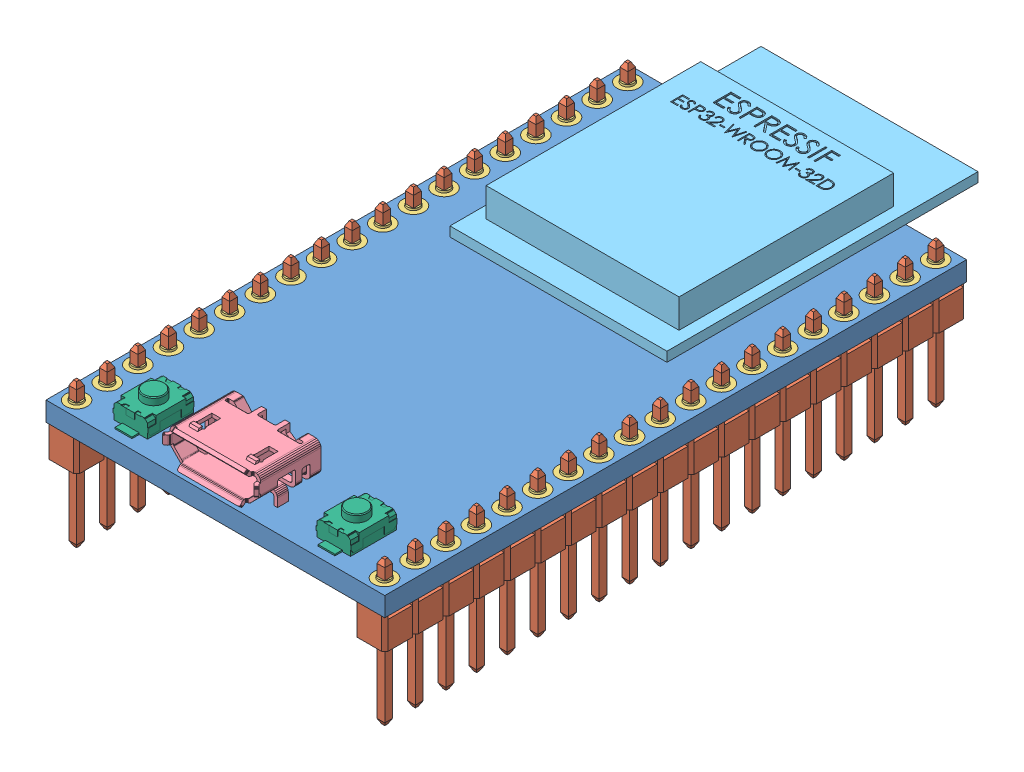
SolidWorks assembly ESP32-WROOM-32D-Assembly, configuration Default. Lengths in mm.
Overall size (28.1 14.23 54.86).
8 component instances, 6 part files, 27 mates.
Components (placement in the parent):
- Main-PCB-1: Main-PCB [Default] x (1 0 0) z (0 1 0) size (28.1 48.26 1.6)
- zl201-19_p2-54_l48-3_w2-54_h8-9-1: zl201-19_p2-54_l48-3_w2-54_h8-9 [Default] at (-12.78 -0.25 22.86) x (0 0 1) z (0 -1 0) size (48.26 2.54 11.94)
- zl201-19_p2-54_l48-3_w2-54_h8-9-2: zl201-19_p2-54_l48-3_w2-54_h8-9 [Default] at (12.78 -0.25 -22.86) x (0 0 -1) z (0 -1 0) size (48.26 2.54 11.94)
- Soldering-Contacts-1: Soldering-Contacts [Default] at (0 1.6 0) x (1 0 0) z (0 1 0) size (27.34 47.52 2)
- ab2_usb_micro_smd.wrl-1: ab2_usb_micro_smd.wrl [Default] at (0 2.585 24.73) x (1 0 0) z (0 1 0) size (8 5.6 3.57)
- ESP32-chip-1: ESP32-chip [Default] at (0 1.6 0) x (1 0 0) z (0 1 0) size (18 25.8 3.2)
- 3x4x2mm_tact_button-1: 3x4x2mm_tact_button [Default] at (9.1347 1.6 18.3459) x (0 0 1) z (-1 0 0) size (5 2 2.9)
- 3x4x2mm_tact_button-2: 3x4x2mm_tact_button [Default] at (-7.7053 1.6 18.3459) x (0 0 1) z (-1 0 0) size (5 2 2.9)
Mates (geometry in assembly coordinates):
- На месте1: in place: plane of Main-PCB-1 through (0 0 0) normal (0 1 0); moOrthogonalPlaneRef_w of Main-PCB-1 through (0 0 0) normal (0 0 -1); plane of Main-PCB-1 through (0 0 0) normal (1 0 0); unknown of Main-PCB-1
- Совпадение1: coincident aligned: 
- Совпадение2: coincident aligned: plane of Деталь1^Сборка1-1 through (0 0 0) normal (0 0 -1)
- Совпадение3: coincident anti-aligned: plane of Деталь1^Сборка1-1 through (0 0 0) normal (1 0 0)
- Совпадение4: coincident aligned: plane of Деталь1^Сборка1-1 through (-14.05 1.6 -24.13) normal (0 0 -1); plane of zl201-19_p2-54_l48-3_w2-54_h8-9-2 through (13.8 -2.54 -24.13) normal (0 0 -1)
- Совпадение5: coincident anti-aligned: plane of Деталь1^Сборка1-1 through (0 0 0) normal (0 -1 0); plane of zl201-19_p2-54_l48-3_w2-54_h8-9-2 through (12.78 0 -22.86) normal (0 1 0)
- Совпадение6: coincident aligned: plane of Деталь1^Сборка1-1 through (14.05 1.6 24.13) normal (1 0 0); plane of zl201-19_p2-54_l48-3_w2-54_h8-9-2 through (14.05 -2.54 -21.84) normal (1 0 0)
- Совпадение7: coincident aligned: plane of Деталь1^Сборка1-1 through (-14.05 1.6 -24.13) normal (0 0 -1); plane of zl201-19_p2-54_l48-3_w2-54_h8-9-1 through (-13.8 -2.54 -24.13) normal (0 0 -1)
- Совпадение8: coincident aligned: plane of Деталь1^Сборка1-1 through (-14.05 1.6 24.13) normal (-1 0 0); plane of zl201-19_p2-54_l48-3_w2-54_h8-9-1 through (-14.05 -2.54 -23.88) normal (-1 0 0)
- Совпадение9: coincident anti-aligned: plane of Деталь1^Сборка1-1 through (0 0 0) normal (0 -1 0); plane of zl201-19_p2-54_l48-3_w2-54_h8-9-1 through (-12.78 0 -22.86) normal (0 1 0)
- На месте2: in place: plane of Main-PCB-1 through (0 1.6 0) normal (0 1 0); plane of ? through (0 1.6 0) normal (0 1 0); plane of Main-PCB-1 through (0 1.6 0) normal (0 1 0); plane of ? through (0 1.6 0) normal (0 0 -1); plane of Main-PCB-1 through (0 1.6 0) normal (0 1 0); plane of ? through (0 1.6 0) normal (1 0 0); plane of Main-PCB-1 through (0 1.6 0) normal (0 1 0); unknown of ?
- Совпадение10: coincident aligned: plane of ?; plane of ?
- Совпадение11: coincident aligned: plane of Деталь1^ESP-WROOM-32D-Сборка-1 through (0 1.6 0) normal (0 0 -1); plane of Олово-Пайки-Ножек^ESP-WROOM-32D-Сборка-1 through (0 1.6 0) normal (0 0 -1)
- Совпадение12: coincident anti-aligned: plane of Деталь1^ESP-WROOM-32D-Сборка-1 through (0 1.6 0) normal (-1 0 0); plane of Олово-Пайки-Ножек^ESP-WROOM-32D-Сборка-1 through (0 1.6 0) normal (1 0 0)
- Расстояние6: distance = 1 mm anti-aligned: plane of Основная-Плата-1 through (0 1.6 0) normal (0 1 0); plane of ab2_usb_micro_smd.wrl-1 through (0 2.6 24.73) normal (0 -1 0)
- Совпадение14: coincident aligned: plane of Основная-Плата-1 through (-14.05 1.6 24.13) normal (0 0 1); plane of ab2_usb_micro_smd.wrl-1 through (0 2.585 24.13) normal (0 0 1)
- Совпадение15: coincident aligned: plane of Основная-Плата-1 through (0 0 0) normal (1 0 0); plane of ab2_usb_micro_smd.wrl-1 through (0 2.585 24.73) normal (1 0 0)
- На месте3: in place: plane of Main-PCB-1 through (0 1.6 0) normal (0 1 0); plane of ? through (0 1.6 0) normal (0 1 0); moOrthogonalPlaneRef_w of Main-PCB-1 through (0 1.6 0) normal (0 1 0); moOrthogonalPlaneRef_w of ? through (0 1.6 0) normal (0 0 -1); plane of Main-PCB-1 through (0 1.6 0) normal (0 1 0); moOrthogonalPlaneRef_w of ? through (0 1.6 0) normal (1 0 0); moOrthogonalPlaneRef_w of Main-PCB-1 through (0 1.6 0) normal (0 1 0); plane of ?
- Совпадение16: coincident aligned: plane of ?; plane of ?
- Совпадение17: coincident aligned: plane of Основная-Плата-1 through (0 1.6 0) normal (0 0 -1); plane of ESP32-chip-1 through (0 1.6 0) normal (0 0 -1)
- Совпадение18: coincident anti-aligned: plane of Основная-Плата-1 through (0 1.6 0) normal (-1 0 0); plane of ESP32-chip-1 through (0 1.6 0) normal (1 0 0)
- Совпадение21: coincident anti-aligned: plane of Основная-Плата-1 through (0 1.6 0) normal (0 1 0); plane of 3x4x2mm_tact_button-1 through (8.4347 1.6 18.6429) normal (0 -1 0)
- Совпадение22: coincident anti-aligned: plane of Основная-Плата-1 through (0 1.6 0) normal (0 1 0); plane of 3x4x2mm_tact_button-2 through (-8.4053 1.6 18.6429) normal (0 -1 0)
- Расстояние3: distance = 1.39 mm aligned: plane of Основная-Плата-1 through (-14.05 1.6 24.13) normal (0 0 1); plane of 3x4x2mm_tact_button-2 through (-9.82 1.6 22.74) normal (0 0 1)
- Расстояние2: distance = 1.39 mm aligned: plane of Основная-Плата-1 through (-14.05 1.6 24.13) normal (0 0 1); plane of 3x4x2mm_tact_button-1 through (7.02 1.6 22.74) normal (0 0 1)
- Расстояние4: distance = 4.23 mm aligned: plane of 3x4x2mm_tact_button-2 through (-9.82 1.6 18.94) normal (-1 0 0); plane of Основная-Плата-1 through (-14.05 1.6 24.13) normal (-1 0 0)
- Расстояние5: distance = 4.23 mm aligned: plane of 3x4x2mm_tact_button-1 through (9.82 1.6 22.74) normal (1 0 0); plane of Основная-Плата-1 through (14.05 1.6 24.13) normal (1 0 0)
